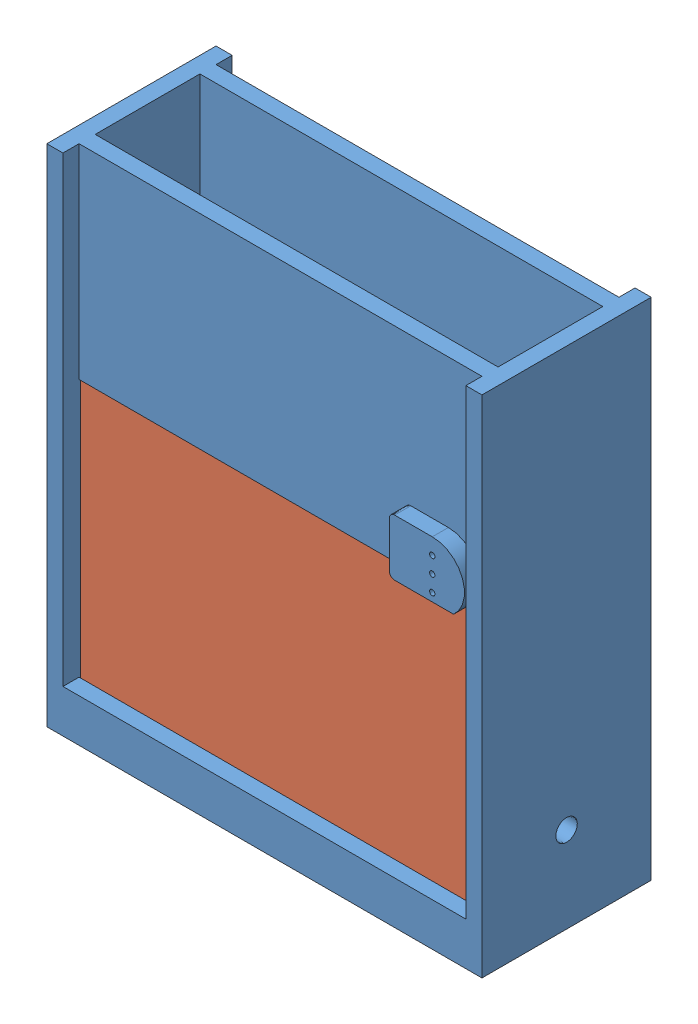
SolidWorks assembly Assem1, configuration Default. Lengths in mm.
Overall size (162 188 63).
2 component instances, 2 part files, 3 mates.
Components (placement in the parent):
- ewk2-1: ewk2 [Default] at origin size (162 188 63)
- glasspane-2: glasspane [Default] at origin size (150 100 50)
Mates (geometry in assembly coordinates):
- Coincident4: coincident anti-aligned: plane of ewk2-1 through (-69 0 21) normal (0 0 1); plane of glasspane-2 through (0 100 21) normal (0 0 -1)
- Coincident5: coincident anti-aligned: plane of ewk2-1 through (75 176 25.5) normal (-1 0 0); plane of glasspane-2 through (75 100 0) normal (1 0 0)
- Coincident6: coincident anti-aligned: plane of ewk2-1 through (-500000 100 -25.5) normal (0 -1 0); plane of glasspane-2 through (0 100 0) normal (0 1 0)
